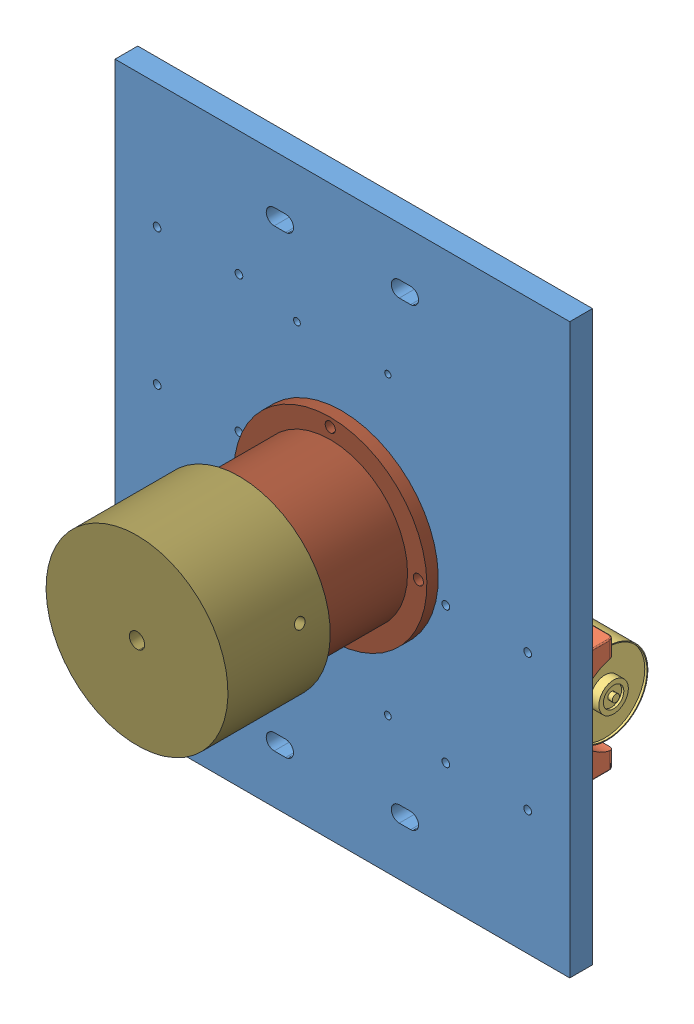
SolidWorks assembly assemblagecompletP2, configuration Défaut. Lengths in mm.
Overall size (200 250 153.06).
75 component instances, 25 part files, 30 mates.
Components (placement in the parent):
- rail-1: rail [Défaut] at (-24.0212 110.7646 2000) size (40 2000 40) (hidden)
- suppport ameliore-1: suppport ameliore [Défaut] at (-123.9247 615.4062 2058.0867) size (200 250 10)
- TigeFilet-1: TigeFilet [Défaut] at (-48.9247 590.4062 2068.0867) x (1 0 0) z (0 1 0) size (5.15 120.44 5.77) (hidden)
- TigeFilet-2: TigeFilet [Défaut] at (1.0753 590.4062 2068.7589) x (-0.923728 -0.383049 0) z (0.383049 -0.923728 0) size (5.15 120.44 5.77) (hidden)
- TigeFilet-3: TigeFilet [Défaut] at (1.0753 390.4062 2068.0961) x (-0.923728 -0.383049 0) z (0.383049 -0.923728 0) size (5.15 120.44 5.77) (hidden)
- TigeFilet-4: TigeFilet [Défaut] at (-48.9247 390.4062 2068.4052) x (-0.728868 0.684654 0) z (-0.684654 -0.728868 0) size (5.15 120.44 5.77) (hidden)
- RoueVAssemblage1-1: RoueVAssemblage1 [Défaut] at (-46.4189 589.2628 1984.8207) x (0.996447 0.084223 0) z (0 0 1) size (15.2 15.2 9) (hidden)
  - RoueV1-1: RoueV1 [Défaut] at (-2.4006 1.3504 10.7) size (15.2 15.2 9)
  - RoueV2-1: RoueV2 [Défaut] at (-2.4006 1.3504 10.7) x (0.999854 -0.017094 0) z (0 0 1) size (10 10 9)
- SousAssemblageMoteurComplet-1: SousAssemblageMoteurComplet [Défaut] at (-133.3233 760.2443 1925.5591) x (1 0 0) z (0 -1 0) size (134.9 58.55 89.71)
  - MoteurEtSupport-1: MoteurEtSupport [Défaut] at (175.3767 115.3051 355.1381) x (0 1 0) z (0 0 -1) size (42.55 57.9 70)
    - SupportMoteur-1: SupportMoteur [Défaut] at (-2.7774 -21.4781 70) size (42.55 52 70)
    - Moteur-1: Moteur [Défaut] at (-4.7774 18.5219 45) x (1 0 0) z (0 -1 0) size (35.75 35.75 56.7)
  - piecemaintientchariot-1: piecemaintientchariot [Défaut] at (103.8575 100.6487 331.5754) size (50 31.79 18)
  - RoulementàBilles-1: RoulementàBilles [Défaut] at (106.8021 108.7409 335.5754) size (4 10 10)
  - Tige_entre_roues-1: Tige_entre_roues [Défaut] at (63.9986 108.7409 335.5754) size (80 3 3)
  - RoueAssemblee-1: RoueAssemblee [Défaut] at (119.9243 114.0834 363.6739) x (-1 0 0) z (0 -0.197919 -0.980218) size (16.9 28.6 28.6)
    - Roue1-1: Roue1 [Défaut] at (-7.3778 0.3244 28.6) size (13 28.6 28.6)
    - Roue2-1: Roue2 [Défaut] at (-7.6778 0.3244 28.6) x (0 -1 0) z (0 0 1) size (19 16.9 19)
  - RoueAssemblee-2: RoueAssemblee [Défaut] at (98.6799 108.2781 306.9773) x (1 0 0) z (0 0.004838 0.999988) size (16.9 28.6 28.6)
    - Roue1-1: Roue1 [Défaut] at (-7.3778 0.3244 28.6) size (13 28.6 28.6)
    - Roue2-1: Roue2 [Défaut] at (-7.6778 0.3244 28.6) x (0 -1 0) z (0 0 1) size (19 16.9 19)
  - PEngrenage-1: PEngrenage [Défaut] at (140.9986 110.5276 310.1381) x (1 0 0) z (0 0.064382 0.997925) size (7.5 9 9)
  - Gengrenage-1: Gengrenage [Défaut] at (143.9986 108.7409 335.5754) x (0 -0.815974 -0.578088) z (0 0.578088 -0.815974) size (42 8.4 42)
- SousAssemblageMoteurComplet-2: SousAssemblageMoteurComplet [Défaut] at (85.4739 220.5681 1925.5591) x (-1 0 0) z (0 1 0) size (134.9 58.55 89.71)
  - MoteurEtSupport-1: MoteurEtSupport [Défaut] at (175.3767 115.3051 355.1381) x (0 1 0) z (0 0 -1) size (42.55 57.9 70)
    - SupportMoteur-1: SupportMoteur [Défaut] at (-2.7774 -21.4781 70) size (42.55 52 70)
    - Moteur-1: Moteur [Défaut] at (-4.7774 18.5219 45) x (1 0 0) z (0 -1 0) size (35.75 35.75 56.7)
  - piecemaintientchariot-1: piecemaintientchariot [Défaut] at (103.8575 100.6487 331.5754) size (50 31.79 18)
  - RoulementàBilles-1: RoulementàBilles [Défaut] at (106.8021 108.7409 335.5754) size (4 10 10)
  - Tige_entre_roues-1: Tige_entre_roues [Défaut] at (63.9986 108.7409 335.5754) size (80 3 3)
  - RoueAssemblee-1: RoueAssemblee [Défaut] at (119.9243 114.0834 363.6739) x (-1 0 0) z (0 -0.197919 -0.980218) size (16.9 28.6 28.6)
    - Roue1-1: Roue1 [Défaut] at (-7.3778 0.3244 28.6) size (13 28.6 28.6)
    - Roue2-1: Roue2 [Défaut] at (-7.6778 0.3244 28.6) x (0 -1 0) z (0 0 1) size (19 16.9 19)
  - RoueAssemblee-2: RoueAssemblee [Défaut] at (98.6799 108.2781 306.9773) x (1 0 0) z (0 0.004838 0.999988) size (16.9 28.6 28.6)
    - Roue1-1: Roue1 [Défaut] at (-7.3778 0.3244 28.6) size (13 28.6 28.6)
    - Roue2-1: Roue2 [Défaut] at (-7.6778 0.3244 28.6) x (0 -1 0) z (0 0 1) size (19 16.9 19)
  - PEngrenage-1: PEngrenage [Défaut] at (140.9986 110.5276 310.1381) x (1 0 0) z (0 0.064382 0.997925) size (7.5 9 9)
  - Gengrenage-1: Gengrenage [Défaut] at (143.9986 108.7409 335.5754) x (0 -0.815974 -0.578088) z (0 0.578088 -0.815974) size (42 8.4 42)
- RoueVAssemblage1-2: RoueVAssemblage1 [Défaut] at (-47.7266 392.8863 1984.6734) x (-0.062339 0.998055 0) z (0 0 1) size (15.2 15.2 9) (hidden)
  - RoueV1-1: RoueV1 [Défaut] at (-2.4006 1.3504 10.7) size (15.2 15.2 9)
  - RoueV2-1: RoueV2 [Défaut] at (-2.4006 1.3504 10.7) x (0.999854 -0.017094 0) z (0 0 1) size (10 10 9)
- RoueVAssemblage1-3: RoueVAssemblage1 [Défaut] at (3.4744 589.0531 1984.6118) x (0.999999 -0.001144 0) z (0 0 1) size (15.2 15.2 9) (hidden)
  - RoueV1-1: RoueV1 [Défaut] at (-2.4006 1.3504 10.7) size (15.2 15.2 9)
  - RoueV2-1: RoueV2 [Défaut] at (-2.4006 1.3504 10.7) x (0.999854 -0.017094 0) z (0 0 1) size (10 10 9)
- RoueVAssemblage1-4: RoueVAssemblage1 [Défaut] at (3.7583 389.7831 1984.8978) x (0.959883 0.2804 0) z (0 0 1) size (15.2 15.2 9) (hidden)
  - RoueV1-1: RoueV1 [Défaut] at (-2.4006 1.3504 10.7) size (15.2 15.2 9)
  - RoueV2-1: RoueV2 [Défaut] at (-2.4006 1.3504 10.7) x (0.999854 -0.017094 0) z (0 0 1) size (10 10 9)
- SupportCamera_Assemblage_V1-1: SupportCamera_Assemblage_V1 [Défaut] at (42.0768 573.8422 2099.1211) x (1 0 0) z (0 -1 0) size (96.67 90 96.67)
  - SupportCamera_Base_V1-1: SupportCamera_Base_V1 [Défaut] at (-66.3336 -31.0344 85) size (85 75 85)
  - SupportCamera_Haut_V1-1: SupportCamera_Haut_V1 [Défaut] at (-66.3336 43.9656 85) x (0.97155 0 -0.236833) z (0.236833 0 0.97155) size (80 45 80)
- CacheChariotAssemblage-2: CacheChariotAssemblage [Défaut] at (353.2431 476.4609 2057.2625) x (0 -1 0) z (-1 0 0) size (262 50 212) (hidden)
  - CacheLateral-1: CacheLateral [Défaut] at (-145.0812 10.8242 271.5) size (262 45 5)
  - CacheLateral2-1: CacheLateral2 [Défaut] at (-140.0812 55.8242 276.5) x (0 0 1) z (0 -1 0) size (202 5 45)
  - CacheLateral-2: CacheLateral [Défaut] at (-145.0812 10.8242 478.5) size (262 45 5)
  - CacheLateral2-2: CacheLateral2 [Défaut] at (111.9188 55.8242 478.5) x (0 0 -1) z (0 -1 0) size (202 5 45)
  - Pièce3^CacheChariotAssemblage-1: Pièce3^CacheChariotAssemblage [Défaut] at origin (virtual)
  - CacheHaut-1: CacheHaut [Défaut] at (116.9188 60.8242 271.5) x (0 0 1) z (0 -1 0) size (212 262 5)
- RoueCodeuse-1: RoueCodeuse [Défaut] at (21.6397 556.1435 2034.3) x (0 0.924225 0.381849) z (-1 0 0) size (28.6 28.6 2)
- assemblage_maintient_entre_rail-1: assemblage_maintient_entre_rail [Défaut] at (28.8853 84.5102 1966.7227) x (1 0 0) z (0 -1 0) size (129.85 48.97 80) (hidden)
  - piece_maintient_entre_rail-1: piece_maintient_entre_rail [Défaut] at (-82.9065 21.2773 40) size (100 18.3 80)
  - Pied-1: Pied [Défaut] at (-92.9065 17.3122 0) x (0.900255 0 -0.435364) z (0.435364 0 0.900255) size (38 45 38)
  - Pied-2: Pied [Défaut] at (-12.9065 17.6532 0) x (0.935976 0 -0.352064) z (0.352064 0 0.935976) size (38 45 38)
  - ecrou_M7-1: ecrou_M7 [Défaut] at (-92.9065 9.05 0) x (0.995992 0 -0.089439) z (0.089439 0 0.995992) size (11 5.5 11)
  - ecrou_M7-2: ecrou_M7 [Défaut] at (-92.9065 -2.574 0) x (0.999221 0 0.039466) z (-0.039466 0 0.999221) size (11 5.5 11)
  - ecrou_M7-3: ecrou_M7 [Défaut] at (-12.9065 9.3498 0) x (0.999844 0 -0.017652) z (0.017652 0 0.999844) size (11 5.5 11)
  - ecrou_M7-4: ecrou_M7 [Défaut] at (-12.9065 -2.2533 0) x (0.99851 0 -0.054578) z (0.054578 0 0.99851) size (11 5.5 11)
- Assemblagefinrail-2: Assemblagefinrail [Défaut] at (14.5886 1090.7646 2011.2866) x (1 0 0) z (0 -1 0) size (118 93 60) (hidden)
  - piece_fin_rail-1: piece_fin_rail [Défaut] at (-8.1098 18.2134 30) size (100 60 60)
  - Pied-1: Pied [Défaut] at (-78.1098 -29.7866 0) size (38 45 38)
  - Pied-2: Pied [Défaut] at (1.8902 -29.7866 0) size (38 45 38)
- Assemblagefinrail-4: Assemblagefinrail [Défaut] at (-61.631 -869.2354 2011.2866) x (-1 0 0) z (0 1 0) size (118 93 60) (hidden)
  - piece_fin_rail-1: piece_fin_rail [Défaut] at (-8.1098 18.2134 30) size (100 60 60)
  - Pied-1: Pied [Défaut] at (-78.1098 -29.7866 0) size (38 45 38)
  - Pied-2: Pied [Défaut] at (1.8902 -29.7866 0) size (38 45 38)
Mates (geometry in assembly coordinates):
- Coaxiale29: concentric: circle of TigeFilet-1; circle of RoueVAssemblage1-1/RoueV2-1
- Coaxiale31: concentric: cylinder of suppport ameliore-1 through (57.5753 420.1062 2068.0867) axis (0 0 1) radius 1.7; circle of SousAssemblageMoteurComplet-1/MoteurEtSupport-1/SupportMoteur-1
- Coïncidente3: coincident: plane of suppport ameliore-1 through (-123.9247 615.4062 2058.0867) normal (0 0 -1); plane of SousAssemblageMoteurComplet-1/MoteurEtSupport-1/SupportMoteur-1 through (65.5753 475.1062 2058.0867) normal (0 0 1)
- Coaxiale40: concentric: circle of suppport ameliore-1; circle of SousAssemblageMoteurComplet-2/MoteurEtSupport-1/SupportMoteur-1
- Coaxiale41: concentric: circle of suppport ameliore-1; cylinder of SousAssemblageMoteurComplet-2/MoteurEtSupport-1/SupportMoteur-1 through (-105.4247 560.7062 2063.0867) axis (0 0 -1) radius 1.2295
- Coïncidente5: coincident: plane of suppport ameliore-1 through (-123.9247 615.4062 2058.0867) normal (0 0 -1); plane of SousAssemblageMoteurComplet-2/MoteurEtSupport-1/SupportMoteur-1 through (-113.4247 505.7062 2058.0867) normal (0 0 1)
- Tangent4: tangent: plane of rail-1 through (-24.0212 1110.7646 2020) normal (0 0 1); cylinder of SousAssemblageMoteurComplet-1/RoueAssemblee-2/Roue1-1 through (-53.3626 424.6688 2034.3) axis (-1 0 0) radius 14.3
- Distance1: distance = 17.5 mm: plane of rail-1 through (-44.0212 1110.7646 2000) normal (-1 0 0); plane of SousAssemblageMoteurComplet-1/piecemaintientchariot-1 through (-26.5212 420.6688 2040.3) normal (-1 0 0)
- Parallèle19: parallel: plane of rail-1 through (-44.0212 1110.7646 2000) normal (-1 0 0); plane of suppport ameliore-1 through (-123.9247 615.4062 2068.0867) normal (-1 0 0)
- Coaxiale44: concentric: circle of suppport ameliore-1; circle of TigeFilet-1
- Perpendiculaire2: perpendicular: plane of rail-1 through (-24.0212 1110.7646 2020) normal (0 0 1); plane of suppport ameliore-1 through (-123.9247 615.4062 2068.0867) normal (0 1 0)
- Coaxiale45: concentric: circle of suppport ameliore-1; circle of TigeFilet-2
- Coaxiale46: concentric: circle of suppport ameliore-1; circle of TigeFilet-4
- Coaxiale47: concentric: circle of suppport ameliore-1; circle of TigeFilet-3
- Coaxiale48: concentric: circle of TigeFilet-4; circle of RoueVAssemblage1-2/RoueV2-1
- Coaxiale52: concentric: circle of TigeFilet-2; circle of RoueVAssemblage1-3/RoueV2-1
- Coaxiale53: concentric: circle of TigeFilet-3; circle of RoueVAssemblage1-4/RoueV2-1
- Coïncidente8: coincident: plane of suppport ameliore-1 through (-123.9247 615.4062 2068.0867) normal (0 0 1); plane of SupportCamera_Assemblage_V1-1/SupportCamera_Base_V1-1 through (-24.2569 488.8422 2068.0867) normal (0 0 -1)
- Distance3: distance = 69.6 mm: point of SupportCamera_Assemblage_V1-1/SupportCamera_Haut_V1-1; cylinder of suppport ameliore-1 through (-3.9247 555.4062 2068.0867) axis (0 0 -1) radius 1.3766
- Distance4: distance = 46.7 mm: point of SupportCamera_Assemblage_V1-1/SupportCamera_Haut_V1-1; cylinder of suppport ameliore-1 through (-69.4247 500.7062 2068.0867) axis (0 0 1) radius 1.7
- Coaxiale56: concentric: circle of SupportCamera_Assemblage_V1-1/SupportCamera_Haut_V1-1; circle of CacheChariotAssemblage-2/CacheHaut-1
- Coaxiale57: concentric: circle of SousAssemblageMoteurComplet-2/Tige_entre_roues-1; circle of RoueCodeuse-1
- Coïncidente9: coincident: plane of rail-1 through (-24.0212 1110.7646 1980) normal (0 0 -1); plane of assemblage_maintient_entre_rail-1/piece_maintient_entre_rail-1 through (-44.0212 124.5102 1980) normal (0 0 1)
- Coïncidente12: coincident: plane of rail-1 through (-24.0212 1110.7646 1980) normal (0 0 -1); plane of assemblage_maintient_entre_rail-1/piece_maintient_entre_rail-1 through (-44.0212 124.5102 1980) normal (0 0 1)
- Coaxiale58: concentric: cylinder of rail-1 through (-40.0212 1110.7646 1984) axis (0 -1 0) radius 4; cylinder of assemblage_maintient_entre_rail-1/piece_maintient_entre_rail-1 through (-40.0212 124.5102 1984) axis (0 1 0) radius 4
- Coïncidente13: coincident: plane of Assemblagefinrail-2/piece_fin_rail-1 through (-44.0212 1110.7646 2020) normal (1 0 0); plane of rail-1 through (-44.0212 1110.7646 2000) normal (-1 0 0)
- Coïncidente14: coincident: plane of rail-1 through (-24.0212 1110.7646 2020) normal (0 0 1); plane of Assemblagefinrail-2/piece_fin_rail-1 through (-44.0212 1110.7646 2020) normal (0 0 -1)
- Coïncidente22: coincident: plane of rail-1 through (-24.0212 -889.2354 2000) normal (0 -1 0); plane of Assemblagefinrail-4/piece_fin_rail-1 through (-53.5212 -889.2354 2115.9011) normal (0 1 0)
- Coïncidente23: coincident: plane of rail-1 through (-44.0212 1110.7646 2000) normal (-1 0 0); plane of Assemblagefinrail-4/piece_fin_rail-1 through (-44.0212 -889.2354 2106.4011) normal (1 0 0)
- Coaxiale61: concentric: cylinder of rail-1 through (-40.0212 1110.7646 2016) axis (0 -1 0) radius 4; cylinder of Assemblagefinrail-4/piece_fin_rail-1 through (-40.0212 -889.2354 2016) axis (0 -1 0) radius 4
